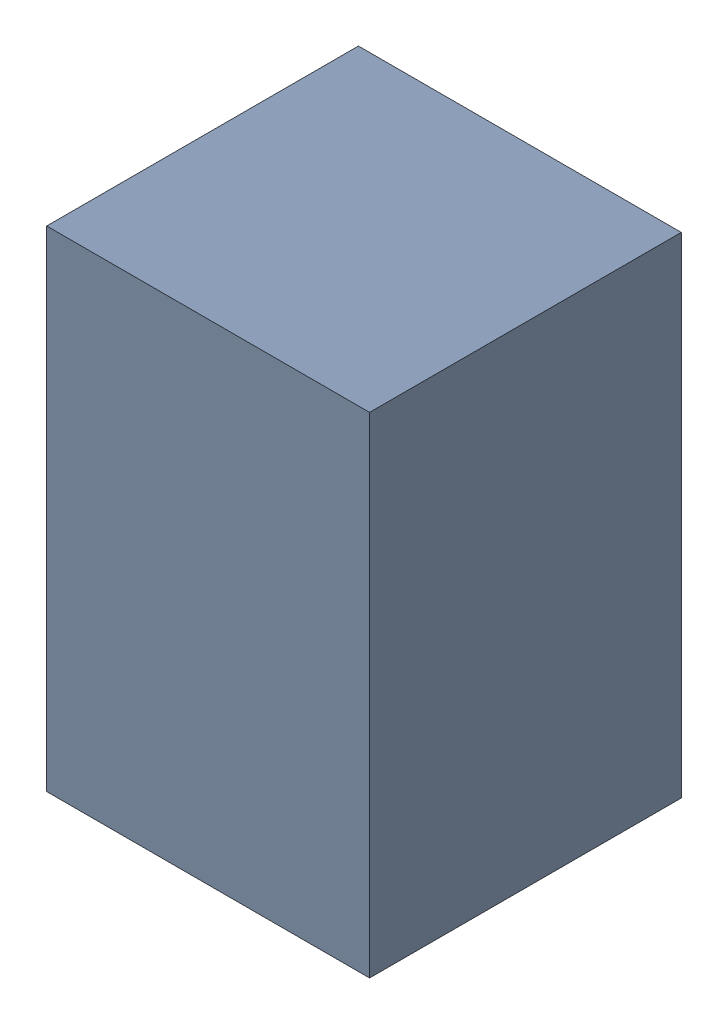
SolidWorks assembly C2, configuration Default. Lengths in mm.
Overall size (1.45 2.2 1.4).
2 component instances, 1 part files, 0 mates.
Components (placement in the parent):
- 580501904-1: 580501904 [Default] at (204.978 100.838 0) size (1.45 2.2 1.4)
  - Extruded_6-1: Extruded_6 [Default] at origin size (1.45 2.2 1.4)
